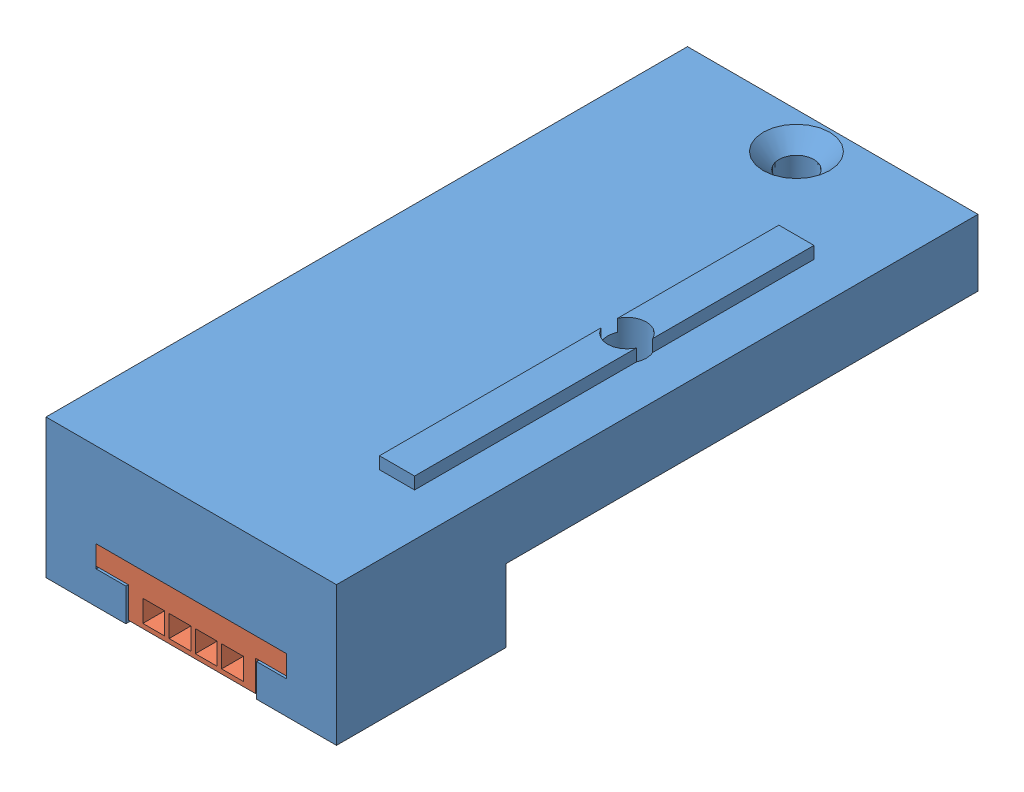
SolidWorks assembly Assem1, configuration Default. Lengths in mm.
Overall size (24 18.14 53).
2 component instances, 2 part files, 3 mates.
Components (placement in the parent):
- pcf8574Support-1: pcf8574Support [Default] at (7.3246 20.5134 21.3643) size (24 12.5 53)
- pcf8574Board-1: pcf8574Board [Default] at (7.3246 25.0134 50.2643) x (0 0 -1) z (0 -1 0) size (48.2 15.7 12)
Mates (geometry in assembly coordinates):
- Coincident1: coincident: plane of pcf8574Support-1 through (15.1746 25.0134 74.3643) normal (0 -1 0); plane of pcf8574Board-1 through (11.3023 25.0134 50.2643) normal (0 1 0)
- Coincident2: coincident: plane of pcf8574Support-1 through (7.3246 20.5134 74.3643) normal (0 0 1); plane of pcf8574Board-1 through (19.1523 23.4134 74.3643) normal (0 0 1)
- Coincident3: coincident anti-aligned: plane of pcf8574Support-1 through (-0.5254 25.0134 74.3643) normal (1 0 0); plane of pcf8574Board-1 through (-0.5254 23.4134 74.3643) normal (-1 0 0)
